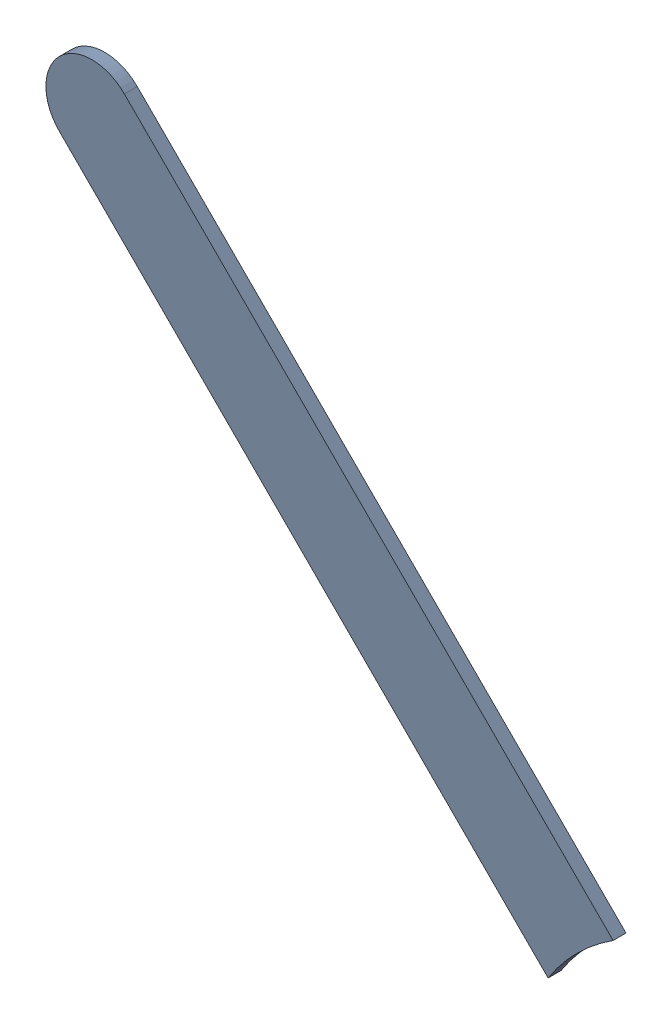
SolidWorks assembly Track (26.416mm,61.2mm)(28.178mm,59.438mm) on Bottom Layer, configuration Predeterminado. Lengths in mm.
Overall size (1.57 1.57 0.04).
2 component instances, 1 part files, 0 mates.
Components (placement in the parent):
- Track (26.416mm,61.2mm)(28.178mm,59.438mm) on Bottom Layer-1-1: Track (26.416mm,61.2mm)(28.178mm,59.438mm) on Bottom Layer-1 [Predeterminado] at (-68.317 -44.187 -0.4013) size (1.57 1.57 0.04)
  - Track (26.416mm,61.2mm)(28.178mm,59.438mm) on Bottom Layer-Part-1-1: Track (26.416mm,61.2mm)(28.178mm,59.438mm) on Bottom Layer-Part-1 [Predeterminado] at origin size (1.57 1.57 0.04)
